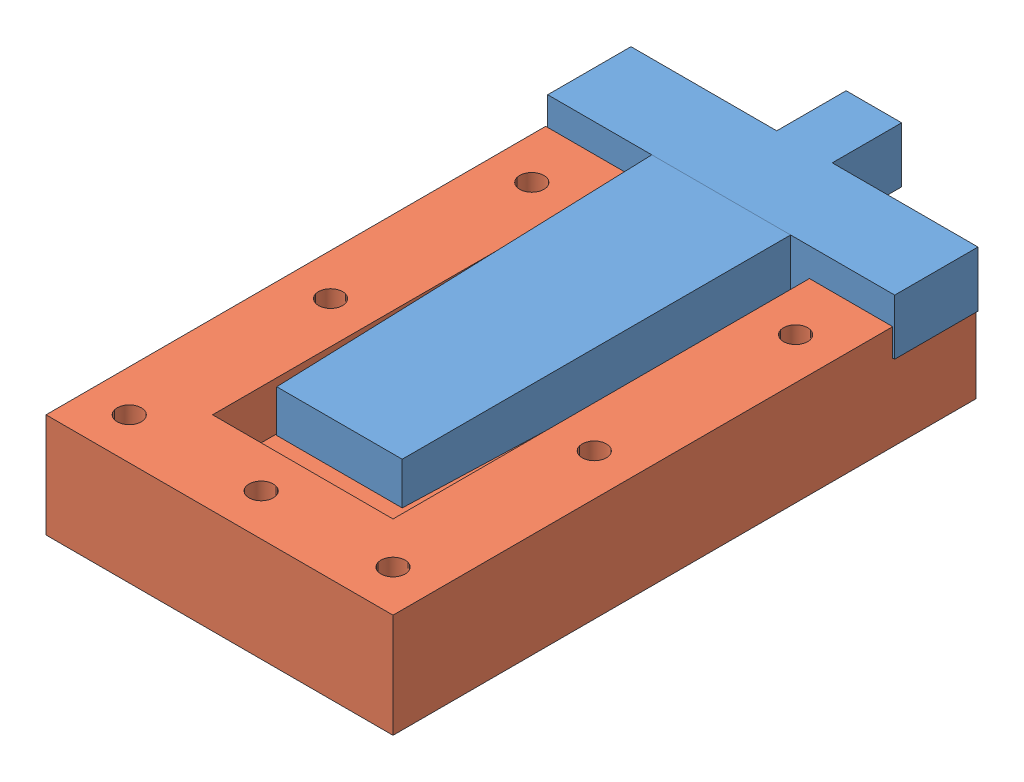
SolidWorks assembly Assem2, configuration ﾃﾞﾌｫﾙﾄ. Lengths in mm.
Overall size (50.2 19 94.08).
2 component instances, 2 part files, 1 mates.
Components (placement in the parent):
- gripper_inside2-1: gripper_inside2 [ﾃﾞﾌｫﾙﾄ] at (-12.8766 -2.5448 48.5) size (50 8 77)
- gripper_outside2-1: gripper_outside2 [ﾃﾞﾌｫﾙﾄ] at (-13.0809 -2.5448 48.5809) size (50 15 84)
Mates (geometry in assembly coordinates):
- 一致1: coincident anti-aligned: plane of gripper_inside2-1 through (-22.8766 -6.5448 60.5) normal (0 -1 0); plane of gripper_outside2-1 through (11.9191 -6.5448 48.5809) normal (0 1 0)
